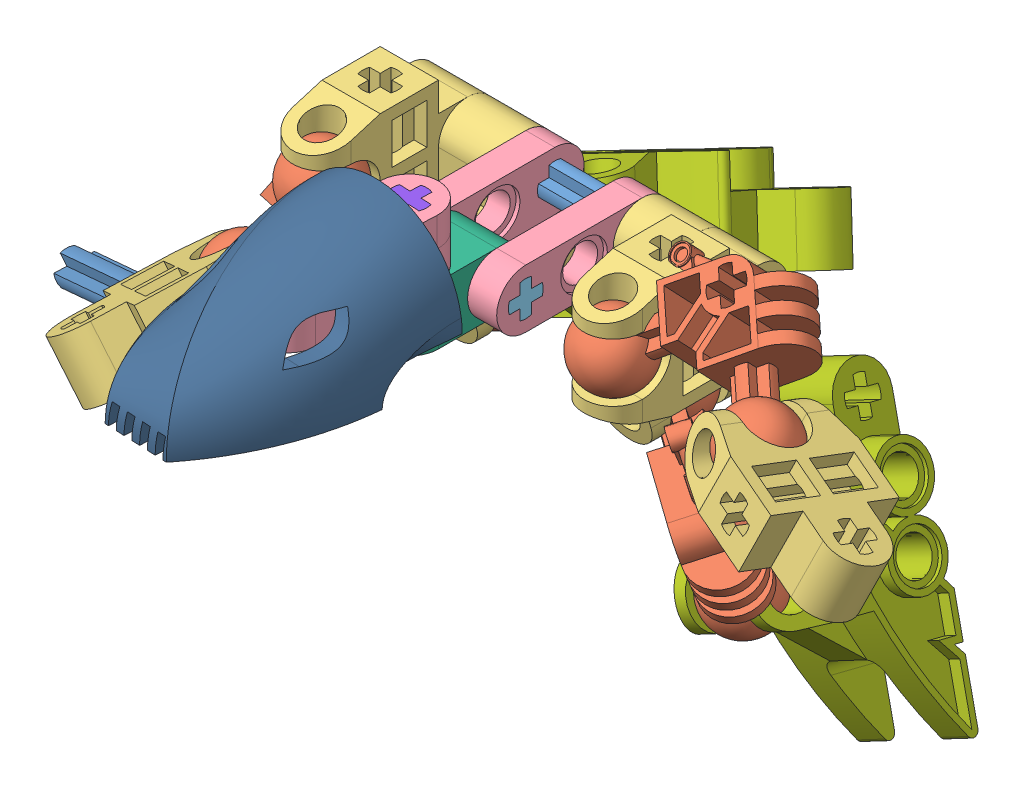
SolidWorks assembly fire guy, configuration Default. Lengths in mm.
Overall size (85.71 50.01 68.49).
23 component instances, 10 part files, 46 mates.
Components (placement in the parent):
- cross axle 6-1: cross axle 6 [Default] at (18.5273 18.929 24.8516) x (0 1 0) z (0 0 1) size (3 30 3)
- link 2x2-1: link 2x2 [Default] at (-13.9568 14.5557 27.366) x (0.498407 0.437332 0.748553) z (-0.291048 -0.728921 0.61965) size (17.5 6 18.1)
- link 2x2-2: link 2x2 [Default] at (-11.9646 10.1989 18.9764) x (0.799188 -0.126988 0.587514) z (0.402455 -0.612952 -0.679941) size (17.5 6 18.1)
- link 2x2-3: link 2x2 [Default] at (23.4054 24.1086 30.5231) x (-0.737812 -0.517958 0.432843) z (0.666503 -0.45756 0.588568) size (17.5 6 18.1)
- link 2x2-4: link 2x2 [Default] at (18.8668 4.4871 29.1888) x (-0.783955 0.444184 -0.433723) z (-0.215997 -0.850135 -0.480225) size (17.5 6 18.1)
- the hand-1: the hand [Default] at (-1.4727 11.429 24.8516) x (0 0 1) z (0 -1 0) size (10 5 15)
- the hand-2: the hand [Default] at (8.5273 11.429 24.8516) x (0 0 -1) z (0 -1 0) size (10 5 15)
- the hand-3: the hand [Default] at (13.5273 18.929 32.3516) x (0 -1 0) z (0 0 1) size (10 5 15)
- the hand-4: the hand [Default] at (-6.4727 18.929 32.3516) x (0 1 0) z (0 0 1) size (10 5 15)
- the hand-5: the hand [Default] at (-16.3018 4.4537 35.6286) x (-0.735477 -0.490898 -0.467004) z (0.352467 0.311448 -0.882478) size (10 5 15)
- the hand-6: the hand [Default] at (31.5002 16.4861 37.4916) x (-0.150792 0.267455 0.951698) z (-0.923814 0.304566 -0.231965) size (10 5 15)
- technic lever 3-1: technic lever 3 [Default] at (6.0273 18.929 29.8516) x (0 0 -1) z (0 -1 0) size (15 2.5 5)
- technic lever 3-2: technic lever 3 [Default] at (-1.4727 18.929 29.8516) x (0 0 -1) z (0 -1 0) size (15 2.5 5)
- cross axle 2-1: cross axle 2 [Default] at (8.5273 18.929 34.8516) x (0 0 1) z (0 -1 0) size (3 10 3)
- cross block 90-1: cross block 90 [Default] at (3.5273 21.429 37.3516) x (0 0 1) z (1 0 0) size (10 5 5)
- the foot-1: the foot [Default] at (-13.7432 -3.0375 3.3271) x (0.858889 0.223995 -0.460582) z (0.419028 -0.824419 0.380458) size (25 15 10)
- the foot-2: the foot [Default] at (18.4053 -8.8523 12.7155) x (-0.445179 0.870157 -0.211289) z (0.894431 0.443326 -0.05878) size (25 15 10)
- cross axle 6-2: cross axle 6 [Default] at (-18.9974 5.4638 37.7414) x (0.352467 0.311448 -0.882478) z (-0.578654 0.813646 0.056037) size (3 30 3)
- technic lever 3-3: technic lever 3 [Default] at (3.3022 21.429 44.8465) x (0.04502 0 -0.998986) z (0.998986 0 0.04502) size (15 2.5 5)
- technic lever 3-4: technic lever 3 [Default] at (3.3022 23.929 44.8465) x (0.04502 0 -0.998986) z (0.998986 0 0.04502) size (15 2.5 5)
- connector peg-cross axle-2: connector peg-cross axle [Default] at (3.5273 16.429 39.8516) x (0.998986 0 0.04502) z (-0.04502 0 0.998986) size (4 10 4)
- connector peg w knob-1: connector peg w knob [Default] at (3.3022 21.429 44.8465) size (4 6 4)
- fire mask-2: fire mask [Default] at (3.4147 18.929 42.349) x (-0.04502 0 0.998986) z (-0.998986 0 -0.04502) size (20.36 10.1 15.04)
Mates (geometry in assembly coordinates):
- Coincident2: coincident aligned: plane of cross axle 6-1 through (18.5273 18.929 24.8516) normal (1 0 0); plane of the hand-3 through (18.5273 18.929 32.3516) normal (1 0 0)
- Coincident3: coincident aligned: circle of cross axle 6-1; circle of the hand-3
- Coincident4: coincident anti-aligned: plane of the hand-2 through (13.5273 11.429 24.8516) normal (1 0 0); plane of the hand-3 through (13.5273 18.929 32.3516) normal (-1 0 0)
- Coincident8: coincident anti-aligned: plane of cross axle 6-1 through (-11.4727 19.429 26.3516) normal (0 1 0); plane of the hand-3 through (18.5273 19.429 32.3516) normal (0 -1 0)
- Coincident9: coincident anti-aligned: cylinder of cross axle 6-1 through (18.5283 18.929 24.8516) axis (-1 0 0) radius 1.5; circle of the hand-2
- Coincident10: coincident anti-aligned: plane of cross axle 6-1 through (-11.4727 19.429 26.3516) normal (0 1 0); plane of the hand-2 through (13.5273 19.429 24.8516) normal (0 -1 0)
- Coincident11: coincident aligned: circle of cross axle 6-1; circle of the hand-4
- Coincident12: coincident anti-aligned: plane of cross axle 6-1 through (-11.4727 17.429 25.3516) normal (0 0 1); plane of the hand-4 through (-11.4727 18.929 25.3516) normal (0 0 -1)
- Coincident14: coincident anti-aligned: plane of the hand-1 through (-6.4727 11.429 24.8516) normal (-1 0 0); plane of the hand-4 through (-6.4727 18.929 32.3516) normal (1 0 0)
- Concentric2: concentric anti-aligned: cylinder of cross axle 6-1 through (18.5283 18.929 24.8516) axis (-1 0 0) radius 1.5; cylinder of the hand-1 through (-6.4727 18.929 24.8516) axis (1 0 0) radius 1.5
- Coincident16: coincident anti-aligned: plane of cross axle 6-1 through (-11.4727 17.429 24.3516) normal (0 0 -1); plane of the hand-1 through (-6.4727 11.429 24.3516) normal (0 0 1)
- Concentric3: concentric: sphere of link 2x2-2; sphere of the hand-1
- Concentric4: concentric: sphere of link 2x2-1; sphere of the hand-4
- Concentric5: concentric: sphere of link 2x2-3; sphere of the hand-3
- Concentric6: concentric: sphere of link 2x2-4; sphere of the hand-2
- Concentric7: concentric: sphere of link 2x2-1; sphere of the hand-5
- Concentric8: concentric: sphere of link 2x2-3; sphere of the hand-6
- Coincident17: coincident anti-aligned: cylinder of cross axle 6-1 through (18.5283 18.929 24.8516) axis (-1 0 0) radius 1.5; circle of technic lever 3-1
- Coincident18: coincident anti-aligned: plane of the hand-2 through (8.5273 11.429 24.8516) normal (-1 0 0); plane of technic lever 3-1 through (8.5273 18.929 29.8516) normal (1 0 0)
- Coincident22: coincident anti-aligned: cylinder of cross axle 6-1 through (18.5283 18.929 24.8516) axis (-1 0 0) radius 1.5; circle of technic lever 3-2
- Coincident23: coincident anti-aligned: plane of the hand-1 through (-1.4727 11.429 24.8516) normal (1 0 0); plane of technic lever 3-2 through (-1.4727 18.929 29.8516) normal (-1 0 0)
- Parallel4: parallel aligned: plane of cross axle 6-1 through (-11.4727 19.429 26.3516) normal (0 1 0); plane of technic lever 3-2 through (-0.2227 21.429 29.8516) normal (0 1 0)
- Coincident25: coincident anti-aligned: circle of technic lever 3-1; cylinder of cross axle 2-1 through (8.5283 18.929 34.8516) axis (-1 0 0) radius 1.5
- Coincident26: coincident aligned: plane of technic lever 3-1 through (8.5273 18.929 29.8516) normal (1 0 0); plane of cross axle 2-1 through (8.5273 18.929 34.8516) normal (1 0 0)
- Parallel5: parallel aligned: plane of technic lever 3-1 through (7.2773 21.429 29.8516) normal (0 1 0); plane of cross axle 2-1 through (-1.4727 19.429 33.3516) normal (0 1 0)
- Coincident28: coincident anti-aligned: cylinder of cross axle 2-1 through (8.5283 18.929 34.8516) axis (-1 0 0) radius 1.5; circle of cross block 90-1
- Coincident29: coincident anti-aligned: plane of technic lever 3-1 through (6.0273 18.929 29.8516) normal (-1 0 0); plane of cross block 90-1 through (6.0273 16.429 37.3516) normal (1 0 0)
- Coincident30: coincident aligned: plane of technic lever 3-2 through (-0.2227 21.429 29.8516) normal (0 1 0); plane of cross block 90-1 through (3.5273 21.429 37.3516) normal (0 1 0)
- Concentric9: concentric: sphere of link 2x2-2; sphere of the foot-1
- Concentric10: concentric: sphere of link 2x2-4; sphere of the foot-2
- Concentric11: concentric anti-aligned: cylinder of the hand-5 through (-22.307 3.2547 35.6399) axis (0.735477 0.490898 0.467004) radius 1.5; cylinder of cross axle 6-2 through (-18.9966 5.4643 37.7419) axis (-0.735477 -0.490898 -0.467004) radius 1.5
- Coincident31: coincident anti-aligned: plane of the hand-5 through (-20.6841 1.3763 35.0586) normal (-0.352467 -0.311448 0.882478); plane of cross axle 6-2 through (-41.7534 -7.887 23.3741) normal (0.352467 0.311448 -0.882478)
- Coincident32: coincident anti-aligned: plane of the hand-5 through (-18.9263 7.3815 35.6137) normal (-0.735477 -0.490898 -0.467004); plane of cross axle 6-2 through (-18.9974 5.4638 37.7414) normal (0.735477 0.490898 0.467004)
- Concentric17: concentric anti-aligned: cylinder of cross block 90-1 through (3.5273 16.429 39.8516) axis (0 1 0) radius 1.5; cylinder of connector peg-cross axle-2 through (3.5273 21.429 39.8516) axis (0 -1 0) radius 1.5
- Coincident42: coincident aligned: plane of cross block 90-1 through (3.5273 16.429 37.3516) normal (0 -1 0); plane of connector peg-cross axle-2 through (3.5273 16.429 39.8516) normal (0 -1 0)
- Concentric18: concentric aligned: cylinder of technic lever 3-3 through (3.5273 22.679 39.8516) axis (0 -1 0) radius 2.5; cylinder of connector peg-cross axle-2 through (3.5273 26.429 39.8516) axis (0 -1 0) radius 1.5
- Coincident43: coincident anti-aligned: plane of technic lever 3-3 through (3.5048 22.679 40.351) normal (0.04502 0 -0.998986); plane of connector peg-cross axle-2 through (3.5048 26.429 40.351) normal (-0.04502 0 0.998986)
- Coincident44: coincident anti-aligned: plane of cross block 90-1 through (3.5273 21.429 37.3516) normal (0 1 0); plane of technic lever 3-3 through (3.3022 21.429 44.8465) normal (0 -1 0)
- Concentric19: concentric aligned: cylinder of technic lever 3-3 through (3.5273 22.679 39.8516) axis (0 -1 0) radius 2.5; cylinder of technic lever 3-4 through (3.5273 25.179 39.8516) axis (0 -1 0) radius 2.5
- Coincident45: coincident anti-aligned: plane of technic lever 3-3 through (3.3022 23.929 44.8465) normal (0 1 0); plane of technic lever 3-4 through (3.3022 23.929 44.8465) normal (0 -1 0)
- Concentric20: concentric aligned: cylinder of technic lever 3-3 through (3.0771 22.679 49.8414) axis (0 -1 0) radius 2.5; cylinder of technic lever 3-4 through (3.0771 25.179 49.8414) axis (0 -1 0) radius 2.5
- Concentric21: concentric aligned: cylinder of technic lever 3-4 through (3.3022 25.179 44.8465) axis (0 -1 0) radius 1.5; cylinder of connector peg w knob-1 through (3.3022 26.429 44.8465) axis (0 -1 0) radius 1.5
- Coincident46: coincident aligned: plane of technic lever 3-4 through (3.3022 26.429 44.8465) normal (0 1 0); plane of connector peg w knob-1 through (3.3022 26.429 44.8465) normal (0 1 0)
- Coincident50: coincident anti-aligned: plane of technic lever 3-4 through (2.8027 25.179 44.824) normal (0.998986 0 0.04502); plane of fire mask-2 through (2.9152 29.0088 42.3265) normal (-0.998986 0 -0.04502)
- Coincident52: coincident aligned: plane of technic lever 3-3 through (3.3022 21.429 44.8465) normal (0 -1 0); plane of fire mask-2 through (3.4147 21.429 42.349) normal (0 -1 0)
- Concentric24: concentric aligned: circle of technic lever 3-3; circle of fire mask-2
